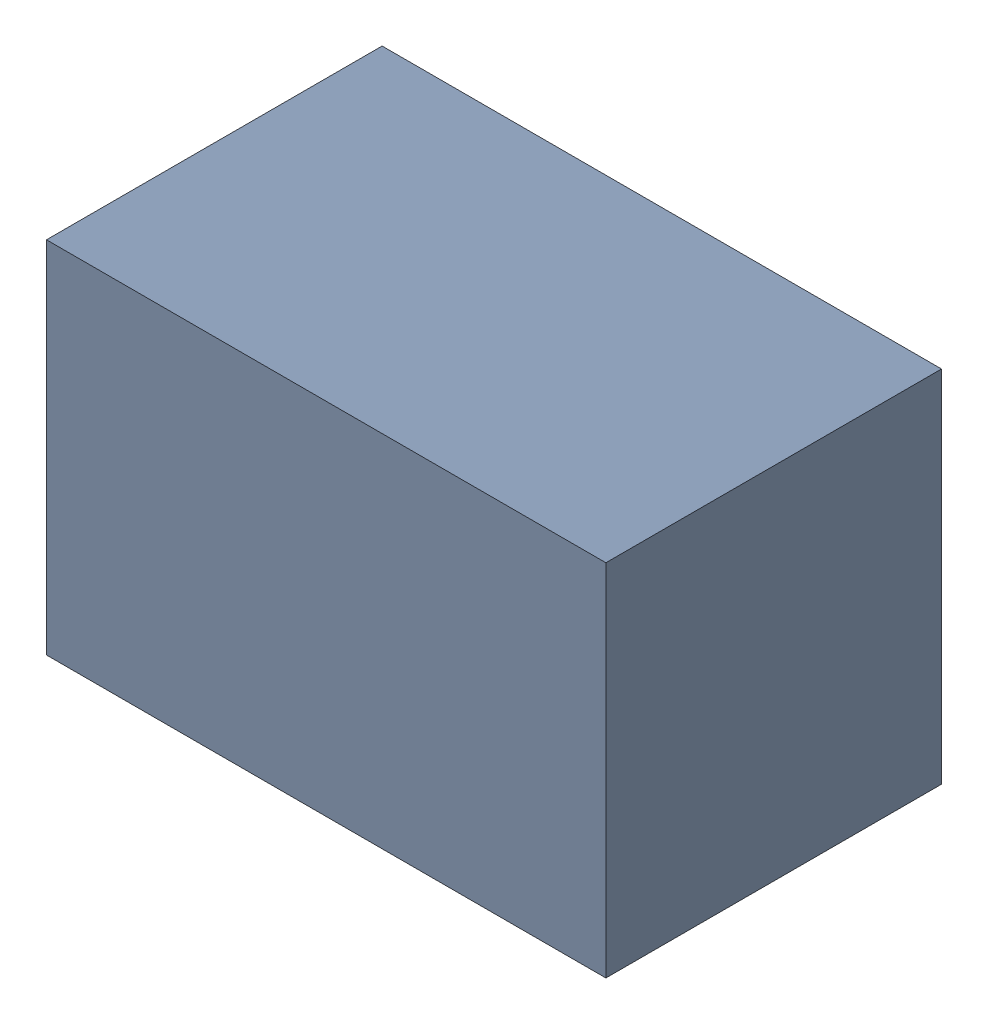
SolidWorks assembly C32, configuration Default. Lengths in mm.
Overall size (2.1 1.35 1.26).
2 component instances, 1 part files, 0 mates.
Components (placement in the parent):
- 407985824-1: 407985824 [Default] at (50.419 29.4386 0.0127) size (2.1 1.35 1.26)
  - Extruded_2-1: Extruded_2 [Default] at origin size (2.1 1.35 1.26)
